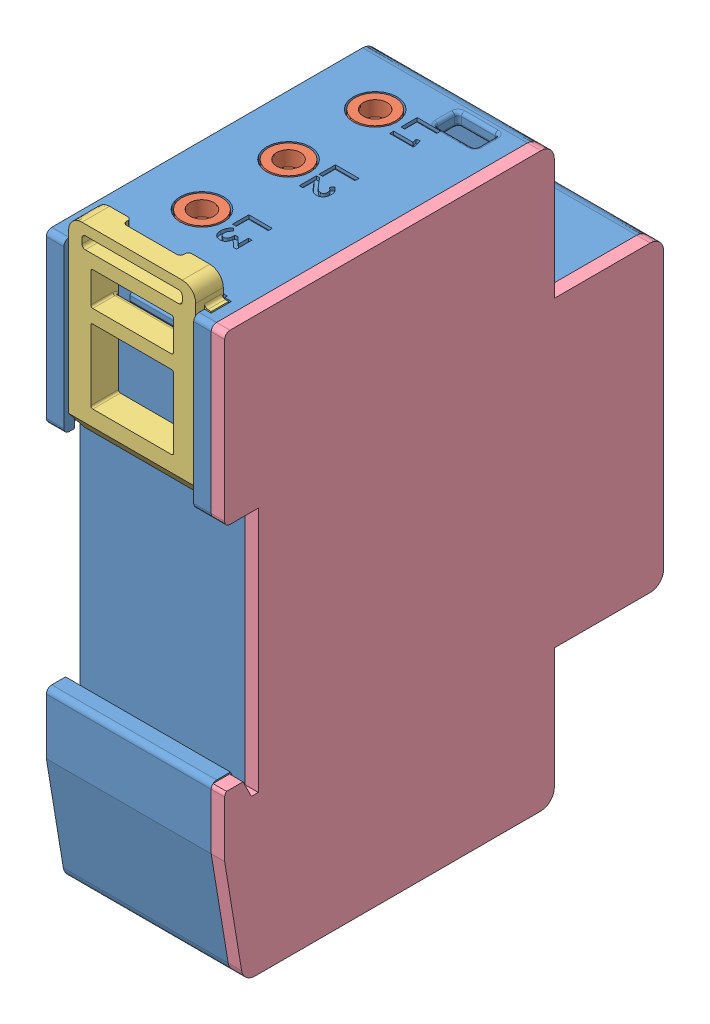
SolidWorks assembly sensor, configuration Default. Lengths in mm.
Overall size (26.5 88.2 65.75).
4 component instances, 4 part files, 6 mates.
Components (placement in the parent):
- sensor_case-1: sensor_case [Default] at (-5.5509 6.493 110.6411) size (24.5 85.01 65.75)
- senzor_vezje-1: senzor_vezje [Default] at (-1.5509 48.553 88.2411) x (0 0 1) z (0 1 0) size (39.8 17.6 82.84)
- senzor_hakeljcek-1: senzor_hakeljcek [Default] at origin size (20.9 28.6 4.1)
- sensor_cover-1: sensor_cover [Default] at (15.6491 88.9293 114.3683) x (0 -1 0) z (0 0 1) size (85 5.3 65.25)
Mates (geometry in assembly coordinates):
- Coincident2: coincident aligned: plane of senzor_ohisje-1 through (18.9491 91.493 110.6411) normal (0 1 0); plane of senzor_vezje-1 through (3.3091 91.493 75.6261) normal (0 1 0)
- Distance2: distance = 0.5 mm anti-aligned: plane of senzor_vezje-1 through (0.1491 88.453 108.1411) normal (0 0 1); plane of senzor_ohisje-1 through (18.9491 6.493 108.6411) normal (0 0 -1)
- Coincident4: coincident anti-aligned: plane of senzor_ohisje-1 through (-1.5509 6.493 110.6411) normal (1 0 0); plane of senzor_vezje-1 through (-1.5509 48.553 88.2411) normal (-1 0 0)
- Coincident9: coincident aligned: plane of senzor_ohisje-1 through (18.9491 91.493 110.6411) normal (0 1 0); plane of senzor_pokrovcek-1 through (20.9491 91.493 68.6411) normal (0 1 0)
- Coincident10: coincident aligned: plane of senzor_ohisje-1 through (-32.1255 23.493 115.6411) normal (0 0 1); plane of senzor_pokrovcek-1 through (20.9491 90.693 115.6411) normal (0 0 1)
- Coincident11: coincident anti-aligned: plane of senzor_ohisje-1 through (18.9491 6.493 110.6411) normal (1 0 0); plane of senzor_pokrovcek-1 through (18.9491 31.793 114.8411) normal (-1 0 0)
